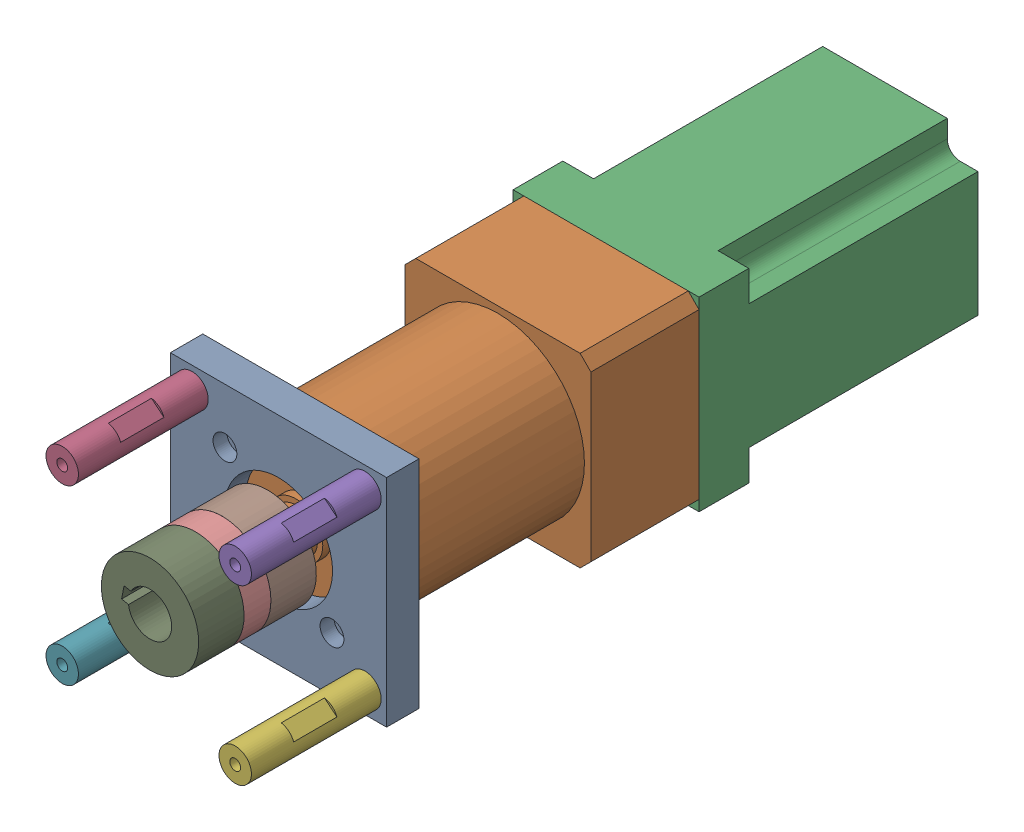
SolidWorks assembly JH-DL151217-011ES, configuration 默认. Lengths in mm.
Overall size (101.12 101.12 340.5).
8 component instances, 5 part files, 15 mates.
Components (placement in the parent):
- JH-DL151217-011E.SLDPRD-1: JH-DL151217-011E.SLDPRD [默认] at origin size (100 100 15)
- JH-减速机士纳-PL80L2-12-P2-S2.SLDPRD-1: JH-减速机士纳-PL80L2-12-P2-S2.SLDPRD [默认] at (0 0 -136.5) size (86 86 179.5)
- JH-86步进电机85H2P7035A4-G.SLDPRD-1: JH-86步进电机85H2P7035A4-G.SLDPRD [默认] at (0 0 -201) size (86 86 160.5)
- JH-DL151217-012E.SLDPRD-1: JH-DL151217-012E.SLDPRD [默认] at (-40 40 45) x (-0.639644 -0.768671 0) z (0 0 1) size (15 15 60)
- JH-DL151217-012E.SLDPRD-2: JH-DL151217-012E.SLDPRD [默认] at (40 40 45) x (-0.639644 -0.768671 0) z (0 0 1) size (15 15 60)
- JH-DL151217-012E.SLDPRD-3: JH-DL151217-012E.SLDPRD [默认] at (40 -40 45) x (-0.639644 -0.768671 0) z (0 0 1) size (15 15 60)
- JH-DL151217-012E.SLDPRD-4: JH-DL151217-012E.SLDPRD [默认] at (-40 -40 45) x (-0.639644 -0.768671 0) z (0 0 1) size (15 15 60)
- JH-三木联轴器AL-075(改建槽尺寸）.SLDPRD-1: JH-三木联轴器AL-075(改建槽尺寸）.SLDPRD [默认] at (0 0 47.2) x (0.188961 0.981985 0) z (0 0 1) size (45 45 54.4)
Mates (geometry in assembly coordinates):
- 重合1: coincident anti-aligned: plane of JH-DL151217-011E.SLDPRD-1 through (0 0 0) normal (0 0 -1); plane of JH-减速机士纳-PL80L2-12-P2-S2.SLDPRD-1 through (0 0 0) normal (0 0 1)
- 同心1: concentric aligned: cylinder of JH-DL151217-011E.SLDPRD-1 through (24.7487 24.7487 15) axis (0 0 1) radius 5.5; cylinder of JH-减速机士纳-PL80L2-12-P2-S2.SLDPRD-1 through (24.7487 24.7487 -15) axis (0 0 1) radius 2.55
- 重合2: coincident anti-aligned: plane of JH-减速机士纳-PL80L2-12-P2-S2.SLDPRD-1 through (0 0 -136.5) normal (0 0 -1); plane of JH-86步进电机85H2P7035A4-G.SLDPRD-1 through (43 43 -136.5) normal (0 0 1)
- 同心2: concentric aligned: cylinder of JH-减速机士纳-PL80L2-12-P2-S2.SLDPRD-1 through (0 0 0) axis (0 0 -1) radius 40; cylinder of JH-86步进电机85H2P7035A4-G.SLDPRD-1 through (0 0 -105) axis (0 0 -1) radius 6.35
- 重合3: coincident anti-aligned: plane of JH-DL151217-011E.SLDPRD-1 through (0 0 15) normal (0 0 1); plane of JH-DL151217-012E.SLDPRD-1 through (-40 40 15) normal (0 0 -1)
- 同心3: concentric aligned: cylinder of JH-DL151217-011E.SLDPRD-1 through (-40 40 0) axis (0 0 -1) radius 3.2; cylinder of JH-DL151217-012E.SLDPRD-1 through (-40 40 75) axis (0 0 -1) radius 7.5
- 同心4: concentric aligned: cylinder of JH-DL151217-011E.SLDPRD-1 through (-40 -40 0) axis (0 0 -1) radius 3.2; cylinder of JH-DL151217-012E.SLDPRD-4 through (-40 -40 75) axis (0 0 -1) radius 7.5
- 重合4: coincident aligned: plane of JH-DL151217-012E.SLDPRD-1 through (-40 40 75) normal (0 0 1); plane of JH-DL151217-012E.SLDPRD-4 through (-40 -40 75) normal (0 0 1)
- 重合5: coincident aligned: plane of JH-DL151217-012E.SLDPRD-1 through (-40 40 75) normal (0 0 1); plane of JH-DL151217-012E.SLDPRD-3 through (40 -40 75) normal (0 0 1)
- 重合6: coincident aligned: plane of JH-DL151217-012E.SLDPRD-1 through (-40 40 75) normal (0 0 1); plane of JH-DL151217-012E.SLDPRD-2 through (40 40 75) normal (0 0 1)
- 同心5: concentric aligned: cylinder of JH-DL151217-011E.SLDPRD-1 through (40 40 0) axis (0 0 -1) radius 3.2; cylinder of JH-DL151217-012E.SLDPRD-2 through (40 40 75) axis (0 0 -1) radius 7.5
- 同心6: concentric aligned: cylinder of JH-DL151217-011E.SLDPRD-1 through (40 -40 0) axis (0 0 -1) radius 3.2; cylinder of JH-DL151217-012E.SLDPRD-3 through (40 -40 75) axis (0 0 -1) radius 7.5
- 同心7: concentric aligned: cylinder of JH-减速机士纳-PL80L2-12-P2-S2.SLDPRD-1 through (0 0 43) axis (0 0 -1) radius 10; cylinder of JH-三木联轴器AL-075(改建槽尺寸）.SLDPRD-1 through (0 0 77.5278) axis (0 0 -1) radius 10
- 同心8: concentric aligned: cylinder of JH-DL151217-011E.SLDPRD-1 through (0 0 15) axis (0 0 -1) radius 25; cylinder of JH-减速机士纳-PL80L2-12-P2-S2.SLDPRD-1 through (0 0 7) axis (0 0 -1) radius 12.5
- 距离1: distance = 5 mm anti-aligned: plane of JH-DL151217-011E.SLDPRD-1 through (0 0 15) normal (0 0 1); plane of JH-三木联轴器AL-075(改建槽尺寸）.SLDPRD-1 through (0 0 20) normal (0 0 -1)
